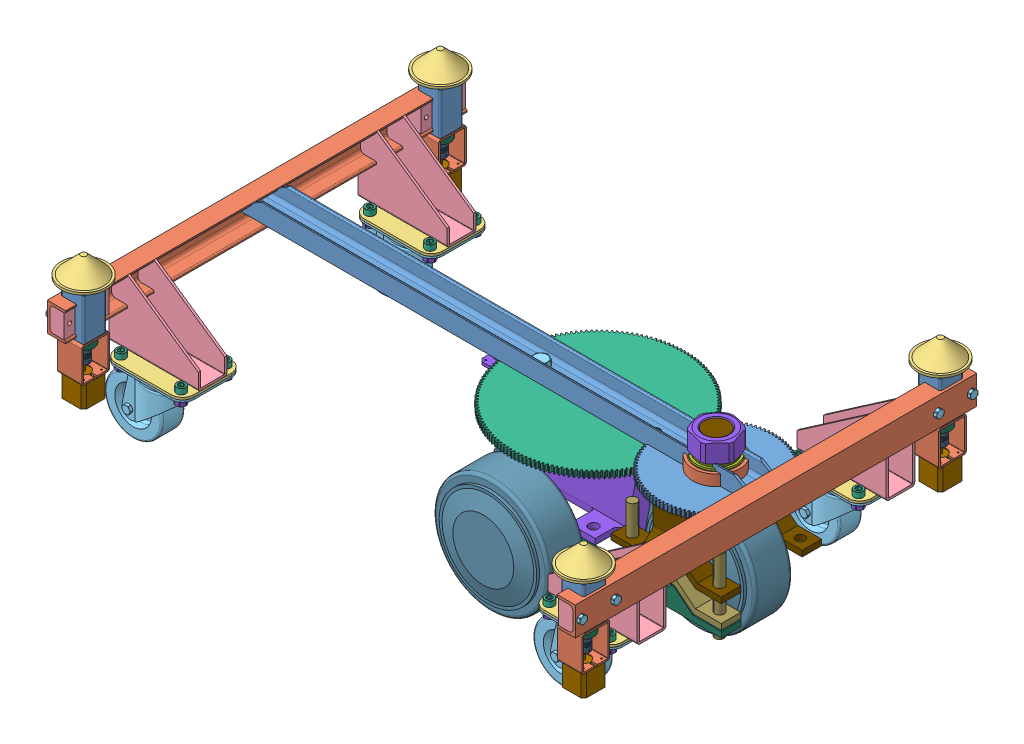
SolidWorks assembly Носитель К3-1, configuration 00. Lengths in mm.
Overall size (950 309 700).
195 component instances, 38 part files, 44 mates.
Components (placement in the parent):
- Каркас несущий К3-1: Каркас несущий К3 [00] at (0 265 0) size (950 309 700)
  - Рама силовая (К2)-1: Рама силовая (К2) [Для смещенного] at origin size (920.8 129.01 700)
    - Хребет продольный-1: Хребет продольный [Смещено вперед] at origin size (912 32 50) (hidden)
    - Балка несущая-1: Балка несущая [00] at (-456 -42.75 0) size (155.33 119.25 700)
      - Швеллер 5У-1: Швеллер 5У [--] at origin size (32 50 700)
      - Кронштейн ленивца-1: Кронштейн ленивца [00] at (82.4347 -94.25 217) size (155.33 119.25 105)
        - Опора ленивца-1: Опора ленивца [--] at origin size (137 4 105)
        - Касынка кронштейна ленивца-1: Касынка кронштейна ленивца [--] at (0 4 0) size (155.33 115.25 50)
      - Кронштейн ленивца-2: Кронштейн ленивца [00] at (82.4347 -94.25 -217) size (155.33 119.25 105)
        - Опора ленивца-1: Опора ленивца [--] at origin size (137 4 105)
        - Касынка кронштейна ленивца-1: Касынка кронштейна ленивца [--] at (0 4 0) size (155.33 115.25 50)
    - Балка несущая-2: Балка несущая [00] at (456 -42.75 0) x (-1 0 0) z (0 0 -1) size (155.33 119.25 700)
      - Швеллер 5У-1: Швеллер 5У [--] at origin size (32 50 700)
      - Кронштейн ленивца-1: Кронштейн ленивца [00] at (82.4347 -94.25 217) size (155.33 119.25 105)
        - Опора ленивца-1: Опора ленивца [--] at origin size (137 4 105)
        - Касынка кронштейна ленивца-1: Касынка кронштейна ленивца [--] at (0 4 0) size (155.33 115.25 50)
      - Кронштейн ленивца-2: Кронштейн ленивца [00] at (82.4347 -94.25 -217) size (155.33 119.25 105)
        - Опора ленивца-1: Опора ленивца [--] at origin size (137 4 105)
        - Касынка кронштейна ленивца-1: Касынка кронштейна ленивца [--] at (0 4 0) size (155.33 115.25 50)
  - АЗ - Колесо ленивец - Tente Alpha 3470 ITP 100 P63-1: АЗ - Колесо ленивец - Tente Alpha 3470 ITP 100 P63 [По умолчанию] at (-373.5653 -137 217) size (202.87 128 202.87)
  - АЗ - Колесо ленивец - Tente Alpha 3470 ITP 100 P63-2: АЗ - Колесо ленивец - Tente Alpha 3470 ITP 100 P63 [По умолчанию] at (373.5653 -137 217) size (202.87 128 202.87)
  - АЗ - Колесо ленивец - Tente Alpha 3470 ITP 100 P63-3: АЗ - Колесо ленивец - Tente Alpha 3470 ITP 100 P63 [По умолчанию] at (373.5653 -137 -217) size (202.87 128 202.87)
  - АЗ - Колесо ленивец - Tente Alpha 3470 ITP 100 P63-4: АЗ - Колесо ленивец - Tente Alpha 3470 ITP 100 P63 [По умолчанию] at (-373.5653 -137 -217) size (202.87 128 202.87)
  - Винты с цилиндрической головкой (ГОСТ 11738-84)-1: Винты с цилиндрической головкой (ГОСТ 11738-84) [Винт М10-(6g)x20 ГОСТ 11738-84] at (-426.0653 -133 255.75) x (0.408379 0 0.912812) z (0 1 0) size (16 16 30.28)
  - Шайбы (ГОСТ 11371-78)-1: Шайбы (ГОСТ 11371-78) [Шайба 10 ГОСТ 11371-78] at (-426.0653 -141.5 255.75) x (0 -1 0) z (0.195759 0 0.980652) size (2 20 20)
  - Гайка (ГОСТ ISO 4032-2014)-1: Гайка (ГОСТ ISO 4032-2014) [Гайка М10 (ГОСТ ISO 4032)] at (-426.0653 -146.7 255.75) x (0.781361 0 0.624079) z (0 1 0) size (16 17.77 8.4)
  - Гайка (ГОСТ ISO 4032-2014)-2: Гайка (ГОСТ ISO 4032-2014) [Гайка М10 (ГОСТ ISO 4032)] at (-321.0653 -146.7 255.75) x (0.884972 0 0.465645) z (0 1 0) size (16 17.77 8.4)
  - Шайбы (ГОСТ 11371-78)-2: Шайбы (ГОСТ 11371-78) [Шайба 10 ГОСТ 11371-78] at (-321.0653 -141.5 255.75) x (0 -1 0) z (0.37706 0 0.926189) size (2 20 20)
  - Винты с цилиндрической головкой (ГОСТ 11738-84)-2: Винты с цилиндрической головкой (ГОСТ 11738-84) [Винт М10-(6g)x20 ГОСТ 11738-84] at (-321.0653 -133 255.75) x (0.573086 0 0.819496) z (0 1 0) size (16 16 30.28)
  - Гайка (ГОСТ ISO 4032-2014)-3: Гайка (ГОСТ ISO 4032-2014) [Гайка М10 (ГОСТ ISO 4032)] at (-321.0653 -146.7 178.25) x (0.964544 0 0.263921) z (0 1 0) size (16 17.77 8.4)
  - Шайбы (ГОСТ 11371-78)-3: Шайбы (ГОСТ 11371-78) [Шайба 10 ГОСТ 11371-78] at (-321.0653 -141.5 178.25) x (0 -1 0) z (0.567856 0 0.823128) size (2 20 20)
  - Винты с цилиндрической головкой (ГОСТ 11738-84)-3: Винты с цилиндрической головкой (ГОСТ 11738-84) [Винт М10-(6g)x20 ГОСТ 11738-84] at (-321.0653 -133 178.25) x (0.736272 0 0.676686) z (0 1 0) size (16 16 30.28)
  - Гайка (ГОСТ ISO 4032-2014)-4: Гайка (ГОСТ ISO 4032-2014) [Гайка М10 (ГОСТ ISO 4032)] at (-426.0653 -146.7 178.25) x (0.999536 0 0.030446) z (0 1 0) size (16 17.77 8.4)
  - Шайбы (ГОСТ 11371-78)-4: Шайбы (ГОСТ 11371-78) [Шайба 10 ГОСТ 11371-78] at (-426.0653 -141.5 178.25) x (0 -1 0) z (0.744998 0 0.667066) size (2 20 20)
  - Винты с цилиндрической головкой (ГОСТ 11738-84)-4: Винты с цилиндрической головкой (ГОСТ 11738-84) [Винт М10-(6g)x20 ГОСТ 11738-84] at (-426.0653 -133 178.25) x (0.874391 0 0.485223) z (0 1 0) size (16 16 30.28)
  - Гайка (ГОСТ ISO 4032-2014)-5: Гайка (ГОСТ ISO 4032-2014) [Гайка М10 (ГОСТ ISO 4032)] at (-426.0653 -146.7 -178.25) x (0.97789 0 -0.209118) z (0 1 0) size (16 17.77 8.4)
  - Шайбы (ГОСТ 11371-78)-5: Шайбы (ГОСТ 11371-78) [Шайба 10 ГОСТ 11371-78] at (-426.0653 -141.5 -178.25) x (0 -1 0) z (0.882737 0 0.469867) size (2 20 20)
  - Винты с цилиндрической головкой (ГОСТ 11738-84)-5: Винты с цилиндрической головкой (ГОСТ 11738-84) [Винт М10-(6g)x20 ГОСТ 11738-84] at (-426.0653 -133 -178.25) x (0.964963 0 0.262386) z (0 1 0) size (16 16 30.28)
  - Гайка (ГОСТ ISO 4032-2014)-6: Гайка (ГОСТ ISO 4032-2014) [Гайка М10 (ГОСТ ISO 4032)] at (-321.0653 -146.7 -178.25) x (0.905941 0 -0.423405) z (0 1 0) size (16 17.77 8.4)
  - Шайбы (ГОСТ 11371-78)-6: Шайбы (ГОСТ 11371-78) [Шайба 10 ГОСТ 11371-78] at (-321.0653 -141.5 -178.25) x (0 -1 0) z (0.965715 0 0.259604) size (2 20 20)
  - Винты с цилиндрической головкой (ГОСТ 11738-84)-6: Винты с цилиндрической головкой (ГОСТ 11738-84) [Винт М10-(6g)x20 ГОСТ 11738-84] at (-321.0653 -133 -178.25) x (0.999241 0 0.038957) z (0 1 0) size (16 16 30.28)
  - Гайка (ГОСТ ISO 4032-2014)-7: Гайка (ГОСТ ISO 4032-2014) [Гайка М10 (ГОСТ ISO 4032)] at (-426.0653 -146.7 -255.75) x (0.807744 0 -0.589534) z (0 1 0) size (16 17.77 8.4)
  - Шайбы (ГОСТ 11371-78)-7: Шайбы (ГОСТ 11371-78) [Шайба 10 ГОСТ 11371-78] at (-426.0653 -141.5 -255.75) x (0 -1 0) z (0.997598 0 0.069276) size (2 20 20)
  - Винты с цилиндрической головкой (ГОСТ 11738-84)-7: Винты с цилиндрической головкой (ГОСТ 11738-84) [Винт М10-(6g)x20 ГОСТ 11738-84] at (-426.0653 -133 -255.75) x (0.988117 0 -0.153703) z (0 1 0) size (16 16 30.28)
  - Гайка (ГОСТ ISO 4032-2014)-8: Гайка (ГОСТ ISO 4032-2014) [Гайка М10 (ГОСТ ISO 4032)] at (-321.0653 -146.7 -255.75) x (0.713458 0 -0.700698) z (0 1 0) size (16 17.77 8.4)
  - Шайбы (ГОСТ 11371-78)-8: Шайбы (ГОСТ 11371-78) [Шайба 10 ГОСТ 11371-78] at (-321.0653 -141.5 -255.75) x (0 -1 0) z (0.997071 0 -0.076488) size (2 20 20)
  - Винты с цилиндрической головкой (ГОСТ 11738-84)-8: Винты с цилиндрической головкой (ГОСТ 11738-84) [Винт М10-(6g)x20 ГОСТ 11738-84] at (-321.0653 -133 -255.75) x (0.955275 0 -0.295719) z (0 1 0) size (16 16 30.28)
  - Гайка (ГОСТ ISO 4032-2014)-9: Гайка (ГОСТ ISO 4032-2014) [Гайка М10 (ГОСТ ISO 4032)] at (321.0653 -146.7 255.75) x (0.647527 0 -0.762043) z (0 1 0) size (16 17.77 8.4)
  - Шайбы (ГОСТ 11371-78)-9: Шайбы (ГОСТ 11371-78) [Шайба 10 ГОСТ 11371-78] at (321.0653 -141.5 255.75) x (0 -1 0) z (0.986146 0 -0.165879) size (2 20 20)
  - Винты с цилиндрической головкой (ГОСТ 11738-84)-9: Винты с цилиндрической головкой (ГОСТ 11738-84) [Винт М10-(6g)x20 ГОСТ 11738-84] at (321.0653 -133 255.75) x (0.924797 0 -0.380462) z (0 1 0) size (16 16 30.28)
  - Гайка (ГОСТ ISO 4032-2014)-10: Гайка (ГОСТ ISO 4032-2014) [Гайка М10 (ГОСТ ISO 4032)] at (426.0653 -146.7 255.75) x (0.624079 0 -0.781361) z (0 1 0) size (16 17.77 8.4)
  - Шайбы (ГОСТ 11371-78)-10: Шайбы (ГОСТ 11371-78) [Шайба 10 ГОСТ 11371-78] at (426.0653 -141.5 255.75) x (0 -1 0) z (0.980652 0 -0.195759) size (2 20 20)
  - Винты с цилиндрической головкой (ГОСТ 11738-84)-10: Винты с цилиндрической головкой (ГОСТ 11738-84) [Винт М10-(6g)x20 ГОСТ 11738-84] at (426.0653 -133 255.75) x (0.912812 0 -0.408379) z (0 1 0) size (16 16 30.28)
  - Гайка (ГОСТ ISO 4032-2014)-11: Гайка (ГОСТ ISO 4032-2014) [Гайка М10 (ГОСТ ISO 4032)] at (321.0653 -146.7 178.25) x (0.647527 0 -0.762043) z (0 1 0) size (16 17.77 8.4)
  - Шайбы (ГОСТ 11371-78)-11: Шайбы (ГОСТ 11371-78) [Шайба 10 ГОСТ 11371-78] at (321.0653 -141.5 178.25) x (0 -1 0) z (0.986146 0 -0.165879) size (2 20 20)
  - Винты с цилиндрической головкой (ГОСТ 11738-84)-11: Винты с цилиндрической головкой (ГОСТ 11738-84) [Винт М10-(6g)x20 ГОСТ 11738-84] at (321.0653 -133 178.25) x (0.924797 0 -0.380462) z (0 1 0) size (16 16 30.28)
  - Гайка (ГОСТ ISO 4032-2014)-12: Гайка (ГОСТ ISO 4032-2014) [Гайка М10 (ГОСТ ISO 4032)] at (426.0653 -146.7 178.25) x (0.713458 0 -0.700698) z (0 1 0) size (16 17.77 8.4)
  - Шайбы (ГОСТ 11371-78)-12: Шайбы (ГОСТ 11371-78) [Шайба 10 ГОСТ 11371-78] at (426.0653 -141.5 178.25) x (0 -1 0) z (0.997071 0 -0.076488) size (2 20 20)
  - Винты с цилиндрической головкой (ГОСТ 11738-84)-12: Винты с цилиндрической головкой (ГОСТ 11738-84) [Винт М10-(6g)x20 ГОСТ 11738-84] at (426.0653 -133 178.25) x (0.955275 0 -0.295719) z (0 1 0) size (16 16 30.28)
  - Гайка (ГОСТ ISO 4032-2014)-13: Гайка (ГОСТ ISO 4032-2014) [Гайка М10 (ГОСТ ISO 4032)] at (321.0653 -146.7 -178.25) x (0.807744 0 -0.589534) z (0 1 0) size (16 17.77 8.4)
  - Шайбы (ГОСТ 11371-78)-13: Шайбы (ГОСТ 11371-78) [Шайба 10 ГОСТ 11371-78] at (321.0653 -141.5 -178.25) x (0 -1 0) z (0.997598 0 0.069276) size (2 20 20)
  - Винты с цилиндрической головкой (ГОСТ 11738-84)-13: Винты с цилиндрической головкой (ГОСТ 11738-84) [Винт М10-(6g)x20 ГОСТ 11738-84] at (321.0653 -133 -178.25) x (0.988117 0 -0.153703) z (0 1 0) size (16 16 30.28)
  - Гайка (ГОСТ ISO 4032-2014)-14: Гайка (ГОСТ ISO 4032-2014) [Гайка М10 (ГОСТ ISO 4032)] at (426.0653 -146.7 -178.25) x (0.905941 0 -0.423405) z (0 1 0) size (16 17.77 8.4)
  - Шайбы (ГОСТ 11371-78)-14: Шайбы (ГОСТ 11371-78) [Шайба 10 ГОСТ 11371-78] at (426.0653 -141.5 -178.25) x (0 -1 0) z (0.965715 0 0.259604) size (2 20 20)
  - Винты с цилиндрической головкой (ГОСТ 11738-84)-14: Винты с цилиндрической головкой (ГОСТ 11738-84) [Винт М10-(6g)x20 ГОСТ 11738-84] at (426.0653 -133 -178.25) x (0.999241 0 0.038957) z (0 1 0) size (16 16 30.28)
  - Гайка (ГОСТ ISO 4032-2014)-15: Гайка (ГОСТ ISO 4032-2014) [Гайка М10 (ГОСТ ISO 4032)] at (321.0653 -146.7 -255.75) x (0.97789 0 -0.209118) z (0 1 0) size (16 17.77 8.4)
  - Шайбы (ГОСТ 11371-78)-15: Шайбы (ГОСТ 11371-78) [Шайба 10 ГОСТ 11371-78] at (321.0653 -141.5 -255.75) x (0 -1 0) z (0.882737 0 0.469867) size (2 20 20)
  - Винты с цилиндрической головкой (ГОСТ 11738-84)-15: Винты с цилиндрической головкой (ГОСТ 11738-84) [Винт М10-(6g)x20 ГОСТ 11738-84] at (321.0653 -133 -255.75) x (0.964963 0 0.262386) z (0 1 0) size (16 16 30.28)
  - Гайка (ГОСТ ISO 4032-2014)-16: Гайка (ГОСТ ISO 4032-2014) [Гайка М10 (ГОСТ ISO 4032)] at (426.0653 -146.7 -255.75) x (0.999536 0 0.030446) z (0 1 0) size (16 17.77 8.4)
  - Шайбы (ГОСТ 11371-78)-16: Шайбы (ГОСТ 11371-78) [Шайба 10 ГОСТ 11371-78] at (426.0653 -141.5 -255.75) x (0 -1 0) z (0.744998 0 0.667066) size (2 20 20)
  - Винты с цилиндрической головкой (ГОСТ 11738-84)-16: Винты с цилиндрической головкой (ГОСТ 11738-84) [Винт М10-(6g)x20 ГОСТ 11738-84] at (426.0653 -133 -255.75) x (0.874391 0 0.485223) z (0 1 0) size (16 16 30.28)
  - Линейный движитель-1: Линейный движитель [00] at (-436 -133 311) x (1 0 0) z (0 1 0) size (78 78 215)
    - 17HS4401 (Nema17)-1: 17HS4401 (Nema17) [--] at origin size (42.3 42.3 63.5)
    - Муфта гибкая-1: Муфта гибкая [--] at (0 0 42.25) size (20 20 26)
    - Винт CS М12х2х150-1: Винт CS М12х2х150 [--] at (0 0 133) x (0.999367 0.035585 0) z (0 0 1) size (12 12.62 100)
    - Упор винта-1: Упор винта [--] at (0 0 57.25) size (14 14 13)
    - Подшипник упорный 8100-1: Подшипник упорный 8100 [--] at (0 0 48.25) x (1 0 0) z (0 -1 0) size (24 9 24)
    - Стопор внутренний до 165мм (ГОСТ 13943-86)-1: Стопор внутренний до 165мм (ГОСТ 13943-86) [Кольцо 24] at (0 0 47.05) size (25.5 26.7 1.2)
    - Обойма под 8100-1: Обойма под 8100 [--] at (0 0 48.25) size (35 35 16.2)
    - Гайка DCM12-1: Гайка DCM12 [Доработка] at (0 0 64.25) x (0 0 1) z (-0.707107 -0.707107 0) size (30.72 41.36 41.36)
    - Профильная труба 35х35х2-1: Профильная труба 35х35х2 [--] at (0 0 74.25) size (35 35 68.75)
    - Заглушка35х35-1: Заглушка35х35 [--] at (0 0 70.25) size (35 35 4)
    - Профильная труба 40х40х2-1: Профильная труба 40х40х2 [--] at (0 0 60.25) size (40 40 72.75)
    - Заглушка 40х40-1: Заглушка 40х40 [--] at (0 0 60.25) size (42.3 48.3 60.25)
    - Уловитель-1: Уловитель [--] at (0 0 143) size (78 78 39)
    - Фиксатор-1: Фиксатор [--] at (-20 -20 60.25) x (0 1 0) z (1 0 0) size (19 41.2 25.1)
    - Фиксатор-2: Фиксатор [--] at (-20 39 60.25) x (0 1 0) z (1 0 0) size (19 41.2 25.1)
  - Болты с шестигранной головкой кт.В (ГОСТ 7798-70)-1: Болты с шестигранной головкой кт.В (ГОСТ 7798-70) [Болт М8-6gx25(S13) ГОСТ 7798-77] at (-460.4 -42.75 340.5) size (30.3 14.2 13)
  - Болты с шестигранной головкой кт.В (ГОСТ 7798-70)-2: Болты с шестигранной головкой кт.В (ГОСТ 7798-70) [Болт М8-6gx25(S13) ГОСТ 7798-77] at (-460.4 -42.75 281.5) x (1 0 0) z (0 -0.158553 0.987351) size (30.3 14.2 13)
  - Линейный движитель-2: Линейный движитель [00] at (-436 -133 -311) x (1 0 0) z (0 1 0) size (78 78 215)
    - 17HS4401 (Nema17)-1: 17HS4401 (Nema17) [--] at origin size (42.3 42.3 63.5)
    - Муфта гибкая-1: Муфта гибкая [--] at (0 0 42.25) size (20 20 26)
    - Винт CS М12х2х150-1: Винт CS М12х2х150 [--] at (0 0 133) x (0.999367 0.035585 0) z (0 0 1) size (12 12.62 100)
    - Упор винта-1: Упор винта [--] at (0 0 57.25) size (14 14 13)
    - Подшипник упорный 8100-1: Подшипник упорный 8100 [--] at (0 0 48.25) x (1 0 0) z (0 -1 0) size (24 9 24)
    - Стопор внутренний до 165мм (ГОСТ 13943-86)-1: Стопор внутренний до 165мм (ГОСТ 13943-86) [Кольцо 24] at (0 0 47.05) size (25.5 26.7 1.2)
    - Обойма под 8100-1: Обойма под 8100 [--] at (0 0 48.25) size (35 35 16.2)
    - Гайка DCM12-1: Гайка DCM12 [Доработка] at (0 0 64.25) x (0 0 1) z (-0.707107 -0.707107 0) size (30.72 41.36 41.36)
    - Профильная труба 35х35х2-1: Профильная труба 35х35х2 [--] at (0 0 74.25) size (35 35 68.75)
    - Заглушка35х35-1: Заглушка35х35 [--] at (0 0 70.25) size (35 35 4)
    - Профильная труба 40х40х2-1: Профильная труба 40х40х2 [--] at (0 0 60.25) size (40 40 72.75)
    - Заглушка 40х40-1: Заглушка 40х40 [--] at (0 0 60.25) size (42.3 48.3 60.25)
    - Уловитель-1: Уловитель [--] at (0 0 143) size (78 78 39)
    - Фиксатор-1: Фиксатор [--] at (-20 -20 60.25) x (0 1 0) z (1 0 0) size (19 41.2 25.1)
    - Фиксатор-2: Фиксатор [--] at (-20 39 60.25) x (0 1 0) z (1 0 0) size (19 41.2 25.1)
  - Болты с шестигранной головкой кт.В (ГОСТ 7798-70)-4: Болты с шестигранной головкой кт.В (ГОСТ 7798-70) [Болт М8-6gx25(S13) ГОСТ 7798-77] at (-460.4 -42.75 -281.5) size (30.3 14.2 13)
  - Болты с шестигранной головкой кт.В (ГОСТ 7798-70)-5: Болты с шестигранной головкой кт.В (ГОСТ 7798-70) [Болт М8-6gx25(S13) ГОСТ 7798-77] at (-460.4 -42.75 -340.5) x (1 0 0) z (0 -0.158553 0.987351) size (30.3 14.2 13)
  - Линейный движитель-5: Линейный движитель [00] at (436 -133 311) x (-1 0 0) z (0 1 0) size (78 78 215)
    - 17HS4401 (Nema17)-1: 17HS4401 (Nema17) [--] at origin size (42.3 42.3 63.5)
    - Муфта гибкая-1: Муфта гибкая [--] at (0 0 42.25) size (20 20 26)
    - Винт CS М12х2х150-1: Винт CS М12х2х150 [--] at (0 0 133) x (0.999367 0.035585 0) z (0 0 1) size (12 12.62 100)
    - Упор винта-1: Упор винта [--] at (0 0 57.25) size (14 14 13)
    - Подшипник упорный 8100-1: Подшипник упорный 8100 [--] at (0 0 48.25) x (1 0 0) z (0 -1 0) size (24 9 24)
    - Стопор внутренний до 165мм (ГОСТ 13943-86)-1: Стопор внутренний до 165мм (ГОСТ 13943-86) [Кольцо 24] at (0 0 47.05) size (25.5 26.7 1.2)
    - Обойма под 8100-1: Обойма под 8100 [--] at (0 0 48.25) size (35 35 16.2)
    - Гайка DCM12-1: Гайка DCM12 [Доработка] at (0 0 64.25) x (0 0 1) z (-0.707107 -0.707107 0) size (30.72 41.36 41.36)
    - Профильная труба 35х35х2-1: Профильная труба 35х35х2 [--] at (0 0 74.25) size (35 35 68.75)
    - Заглушка35х35-1: Заглушка35х35 [--] at (0 0 70.25) size (35 35 4)
    - Профильная труба 40х40х2-1: Профильная труба 40х40х2 [--] at (0 0 60.25) size (40 40 72.75)
    - Заглушка 40х40-1: Заглушка 40х40 [--] at (0 0 60.25) size (42.3 48.3 60.25)
    - Уловитель-1: Уловитель [--] at (0 0 143) size (78 78 39)
    - Фиксатор-1: Фиксатор [--] at (-20 -20 60.25) x (0 1 0) z (1 0 0) size (19 41.2 25.1)
    - Фиксатор-2: Фиксатор [--] at (-20 39 60.25) x (0 1 0) z (1 0 0) size (19 41.2 25.1)
  - Болты с шестигранной головкой кт.В (ГОСТ 7798-70)-10: Болты с шестигранной головкой кт.В (ГОСТ 7798-70) [Болт М8-6gx25(S13) ГОСТ 7798-77] at (460.4 -42.75 281.5) x (-1 0 0) z (0 0 -1) size (30.3 14.2 13)
  - Болты с шестигранной головкой кт.В (ГОСТ 7798-70)-11: Болты с шестигранной головкой кт.В (ГОСТ 7798-70) [Болт М8-6gx25(S13) ГОСТ 7798-77] at (460.4 -42.75 340.5) x (-1 0 0) z (0 -0.158553 -0.987351) size (30.3 14.2 13)
  - Линейный движитель-7: Линейный движитель [00] at (436 -133 -311) x (-1 0 0) z (0 1 0) size (78 78 215)
    - 17HS4401 (Nema17)-1: 17HS4401 (Nema17) [--] at origin size (42.3 42.3 63.5)
    - Муфта гибкая-1: Муфта гибкая [--] at (0 0 42.25) size (20 20 26)
    - Винт CS М12х2х150-1: Винт CS М12х2х150 [--] at (0 0 133) x (0.999367 0.035585 0) z (0 0 1) size (12 12.62 100)
    - Упор винта-1: Упор винта [--] at (0 0 57.25) size (14 14 13)
    - Подшипник упорный 8100-1: Подшипник упорный 8100 [--] at (0 0 48.25) x (1 0 0) z (0 -1 0) size (24 9 24)
    - Стопор внутренний до 165мм (ГОСТ 13943-86)-1: Стопор внутренний до 165мм (ГОСТ 13943-86) [Кольцо 24] at (0 0 47.05) size (25.5 26.7 1.2)
    - Обойма под 8100-1: Обойма под 8100 [--] at (0 0 48.25) size (35 35 16.2)
    - Гайка DCM12-1: Гайка DCM12 [Доработка] at (0 0 64.25) x (0 0 1) z (-0.707107 -0.707107 0) size (30.72 41.36 41.36)
    - Профильная труба 35х35х2-1: Профильная труба 35х35х2 [--] at (0 0 74.25) size (35 35 68.75)
    - Заглушка35х35-1: Заглушка35х35 [--] at (0 0 70.25) size (35 35 4)
    - Профильная труба 40х40х2-1: Профильная труба 40х40х2 [--] at (0 0 60.25) size (40 40 72.75)
    - Заглушка 40х40-1: Заглушка 40х40 [--] at (0 0 60.25) size (42.3 48.3 60.25)
    - Уловитель-1: Уловитель [--] at (0 0 143) size (78 78 39)
    - Фиксатор-1: Фиксатор [--] at (-20 -20 60.25) x (0 1 0) z (1 0 0) size (19 41.2 25.1)
    - Фиксатор-2: Фиксатор [--] at (-20 39 60.25) x (0 1 0) z (1 0 0) size (19 41.2 25.1)
  - Болты с шестигранной головкой кт.В (ГОСТ 7798-70)-14: Болты с шестигранной головкой кт.В (ГОСТ 7798-70) [Болт М8-6gx25(S13) ГОСТ 7798-77] at (460.4 -42.75 -340.5) x (-1 0 0) z (0 0 -1) size (30.3 14.2 13)
  - Болты с шестигранной головкой кт.В (ГОСТ 7798-70)-15: Болты с шестигранной головкой кт.В (ГОСТ 7798-70) [Болт М8-6gx25(S13) ГОСТ 7798-77] at (460.4 -42.75 -281.5) x (-1 0 0) z (0 -0.158553 -0.987351) size (30.3 14.2 13)
  - Шестерня большая-2: Шестерня большая [Z150] at (150 -39.99 0) x (0 -1 0) z (0 0 -1) size (87 303.96 304) (hidden)
  - Болты с шестигранной головкой кт.В (ГОСТ 7798-70)-18: Болты с шестигранной головкой кт.В (ГОСТ 7798-70) [*Болт М16-6gx18(S24) ГОСТ 7798-77] at (50 -35.59 0) x (0 -1 0) z (-0.995564 0 0.094084) size (28 26.2 24) (hidden)
  - Болты с шестигранной головкой кт.В (ГОСТ 7798-70)-19: Болты с шестигранной головкой кт.В (ГОСТ 7798-70) [*Болт М16-6gx18(S24) ГОСТ 7798-77] at (250 -35.59 0) x (0 -1 0) z (-0.959995 0 0.280017) size (28 26.2 24) (hidden)
- Подшипник 2007910А (72х50х15)-1: Подшипник 2007910А (72х50х15) [--] at (150 202.01 0) x (0 1 0) z (-0.845753 0 0.533575) size (15 72 72) (hidden)
- Кронштейн ступицы поворотной-1: Кронштейн ступицы поворотной [00] at (150 199.51 0) size (372.3 178 210.07) (hidden)
  - Каретка-1: Каретка [--] at origin size (372.3 98.5 202)
  - Обойма 2007910А (2шт)-1: Обойма 2007910А (2шт) [--] at (0 -2.5 0) x (0 -1 0) z (-0.634197 0 -0.773171) size (47 82 82)
  - Линейный подшипник (16х30х40)-1: Линейный подшипник (16х30х40) [--] at (-76 -63.5 84) x (-0.966713 0 0.255864) z (0 -1 0) size (30 30 40)
  - Линейный подшипник (16х30х40)-2: Линейный подшипник (16х30х40) [--] at (76 -63.5 84) x (-0.901172 0 0.433461) z (0 -1 0) size (30 30 40)
  - Линейный подшипник (16х30х40)-3: Линейный подшипник (16х30х40) [--] at (76 -63.5 -84) x (-0.786541 0 0.617538) z (0 -1 0) size (30 30 40)
  - Линейный подшипник (16х30х40)-4: Линейный подшипник (16х30х40) [--] at (-76 -63.5 -84) x (-0.619852 0 0.784719) z (0 -1 0) size (30 30 40)
  - Пружина 22х22х2-1: Пружина 22х22х2 [--] at (76 -93.75 -84) x (-0.837169 0 -0.546944) z (-0.546944 0 0.837169) size (24 22 24.59)
  - Пружина 22х22х2-2: Пружина 22х22х2 [--] at (-76 -93.75 -84) x (-0.925243 0 -0.379375) z (-0.379375 0 0.925243) size (24 22 24.59)
  - Пружина 22х22х2-3: Пружина 22х22х2 [--] at (-76 -93.75 84) x (-0.985271 0 -0.170998) z (-0.170998 0 0.985271) size (24 22 24.59)
  - Пружина 22х22х2-4: Пружина 22х22х2 [--] at (76 -93.75 84) x (-0.997902 0 0.064746) z (0.064746 0 0.997902) size (24 22 24.59)
  - Верхний кронштейн К2-1: Верхний кронштейн К2 [--] at (0 -99.5 -67) size (192 129 34)
  - Верхний кронштейн К2-2: Верхний кронштейн К2 [--] at (0 -99.5 101) size (192 129 34)
  - Шайбы (ГОСТ 11371-78)-1: Шайбы (ГОСТ 11371-78) [Шайба 16 ГОСТ 11371-78] at (76 -42 -84) x (0 -1 0) z (0 0 1) size (3 30 30)
  - Гайка (ГОСТ ISO 4032-2014)-1: Гайка (ГОСТ ISO 4032-2014) [Гайка М16 (ГОСТ ISO 4032)] at (76 -33.1 -84) x (0.816213 0 0.577751) z (0 1 0) size (24 26.75 14.8)
  - Гайка (ГОСТ ISO 4032-2014)-2: Гайка (ГОСТ ISO 4032-2014) [Гайка М16 (ГОСТ ISO 4032)] at (-76 -33.1 -84) x (0.910468 0 0.413579) z (0 1 0) size (24 26.75 14.8)
  - Шайбы (ГОСТ 11371-78)-2: Шайбы (ГОСТ 11371-78) [Шайба 16 ГОСТ 11371-78] at (-76 -42 -84) x (0 -1 0) z (0.188455 0 0.982082) size (3 30 30)
  - Гайка (ГОСТ ISO 4032-2014)-4: Гайка (ГОСТ ISO 4032-2014) [Гайка М16 (ГОСТ ISO 4032)] at (-76 -33.1 84) x (0.978217 0 0.207583) z (0 1 0) size (24 26.75 14.8)
  - Шайбы (ГОСТ 11371-78)-4: Шайбы (ГОСТ 11371-78) [Шайба 16 ГОСТ 11371-78] at (-76 -42 84) x (0 -1 0) z (0.395734 0 0.918365) size (3 30 30)
  - Гайка (ГОСТ ISO 4032-2014)-6: Гайка (ГОСТ ISO 4032-2014) [Гайка М16 (ГОСТ ISO 4032)] at (76 -33.1 84) x (0.999621 0 -0.027527) z (0 1 0) size (24 26.75 14.8)
  - Шайбы (ГОСТ 11371-78)-6: Шайбы (ГОСТ 11371-78) [Шайба 16 ГОСТ 11371-78] at (76 -42 84) x (0 -1 0) z (0.6 0 0.8) size (3 30 30)
  - 17HS4401 (Nema17)-1: 17HS4401 (Nema17) [--] at (-165 0 0) x (1 0 0) z (0 1 0) size (42.3 42.3 63.5)
- Шестерня малая-4: Шестерня малая [DIN - Spur gear 2M 15T 20PA 10FW ---S15B15H23L5N] at (-15 215.01 0) x (0 1 0) z (0.147192 0 0.989108) size (23 33.72 33.9) (hidden)
- Мотор-колесо ZLLG80ASM800-2: Мотор-колесо ZLLG80ASM800 [1 крепление] at (150 100.01 154.5) x (0 0 1) z (0 1 0) size (133 200 200) (hidden)
- Прижим К2-1: Прижим К2 [--] at (150 100.01 101) size (192 37 34) (hidden)
- Гайка (ГОСТ ISO 4032-2014)-1: Гайка (ГОСТ ISO 4032-2014) [Гайка М16 (ГОСТ ISO 4032)] at (226 54.61 84) x (-0.815496 0 0.578763) z (0 -1 0) size (24 26.75 14.8) (hidden)
- Гайка (ГОСТ ISO 4032-2014)-2: Гайка (ГОСТ ISO 4032-2014) [Гайка М16 (ГОСТ ISO 4032)] at (74 54.61 84) x (-0.691813 0 0.722077) z (0 -1 0) size (24 26.75 14.8) (hidden)
- Гайка (ГОСТ ISO 4032-2014)-5: Гайка (ГОСТ ISO 4032-2014) [Гайка М16 (ГОСТ ISO 4032)] at (74 54.61 -84) x (-0.691813 0 0.722077) z (0 -1 0) size (24 26.75 14.8) (hidden)
- Прижим К2-2: Прижим К2 [--] at (150 100.01 -67) size (192 37 34) (hidden)
- Мотор-колесо ZLLG80ASM800-3: Мотор-колесо ZLLG80ASM800 [1 крепление] at (150 100.01 -154.5) x (0 0 -1) z (0 1 0) size (133 200 200) (hidden)
- Гайка (ГОСТ ISO 4032-2014)-6: Гайка (ГОСТ ISO 4032-2014) [Гайка М16 (ГОСТ ISO 4032)] at (226 54.61 -84) x (-0.815496 0 0.578763) z (0 -1 0) size (24 26.75 14.8) (hidden)
- Подшипник 2007910А (72х50х15)-2: Подшипник 2007910А (72х50х15) [--] at (150 197.01 0) x (0 -1 0) z (-0.971836 0 0.235658) size (15 72 72) (hidden)
- Кольцо ступицы-1: Кольцо ступицы [--] at (150 177.01 0) x (-0.975842 0 0.218478) z (0.218478 0 0.975842) size (61.75 5 61.75) (hidden)
- Гайка (ГОСТ ISO 4032-2014)-9: Гайка (ГОСТ ISO 4032-2014) [Гайка М42 (ГОСТ ISO 4032)] at (150 160.01 0) x (-0.987419 0 0.158123) z (0 -1 0) size (65 71.3 34) (hidden)
- Привод поворотный (мод 2)-1: Привод поворотный (мод 2) [00] at (356.4 100 0) x (0 0 -1) z (1 0 0) size (232.47 289 236.15)
  - Мотор-колесо ZLLG80ASM800-1: Мотор-колесо ZLLG80ASM800 [По умолчанию] x (1 0 0) z (0 1 0) size (175 200 200)
  - Верхний кронштейн К2-1: Верхний кронштейн К2 [--] at (-53.5 0 0) x (0 0 -1) z (1 0 0) size (192 129 34)
  - Прижим К2-1: Прижим К2 [--] at (-53.5 0 0) x (0 0 -1) z (1 0 0) size (192 37 34)
  - Пружина 14х30-1: Пружина 14х30 [--] at (-70.5 -16 -76) size (22.41 30 22.54)
  - Кулак-1: Кулак [--] at (-87.5 14 0) x (0 0 -1) z (1 0 0) size (232.15 174 175)
  - Подшипник 2007910А (72х50х15)-1: Подшипник 2007910А (72х50х15) [--] at (0 130 0) x (0 -1 0) z (0 0 1) size (15 72 72)
  - Подшипник 2007910А (72х50х15)-3: Подшипник 2007910А (72х50х15) [--] at (0 135 0) x (0 1 0) z (-0.408326 0 0.912836) size (15 72 72)
  - Половинная звезда z100(2)-2: Половинная звезда z100(2) [DIN - Spur gear 2M 100T 20PA 10FW ---S100A75H50L0.2N] at (0 128 0) x (0 -1 0) z (0 0 1) size (41.2 232.47 201.57)
  - Обойма ступицы-1: Обойма ступицы [--] at (0 115 0) size (82 29 82)
  - Кольцо ступицы-1: Кольцо ступицы [--] at (0 155 0) x (0.827904 0 0.56087) z (-0.56087 0 0.827904) size (61.75 5 61.75)
  - Гайка (ГОСТ ISO 4032-2014)-1: Гайка (ГОСТ ISO 4032-2014) [Гайка М42 (ГОСТ ISO 4032)] at (0 172 0) x (-0.974958 0 -0.222391) z (0 -1 0) size (65 71.3 34)
  - Шестерня малая-1: Шестерня малая [DIN - Spur gear 2M 15T 20PA 10FW ---S15B15H23L5N] at (0 118 -115) x (0 1 0) z (0 0 1) size (23 33.72 33.9)
  - 17HS4401 (Nema17)-1: 17HS4401 (Nema17) [--] at (0 105 -115) x (0 0 -1) z (0 1 0) size (42.3 42.3 63.5)
Mates (geometry in assembly coordinates):
- Касательность1: tangent: cylinder of Каркас несущий К3-1/АЗ - Колесо ленивец - Tente Alpha 3470 ITP 100 P63-2 through (323.5653 50 197) axis (0 0 1) radius 50; plane of assembly through (0 0 0) normal (0 1 0)
- Параллельность1: parallel: plane of Каркас несущий К3-1/Шестерня большая-2 through (150 225.01 0) normal (0 1 0)
- Совпадение1: coincident: plane of Каркас несущий К3-1/Рама силовая (К2)-1/Хребет продольный-1 through (0 265 0) normal (0 0 1); plane of assembly through (0 0 0) normal (0 0 1)
- Совпадение2: coincident: plane of Каркас несущий К3-1/Рама силовая (К2)-1/Хребет продольный-1 through (0 265 0) normal (1 0 0); plane of assembly through (0 0 0) normal (1 0 0)
- Совпадение3: coincident: plane of Каркас несущий К3-1/Шестерня большая-2 through (136.8029 217.01 31.9421) normal (0 -1 0); plane of Подшипник 2007910А (72х50х15)-1 through (131.5591 217.01 -29.2301) normal (0 1 0)
- Концентричный1: concentric: cylinder of Подшипник 2007910А (72х50х15)-1 through (150 -797.99 0) axis (0 -1 0) radius 25; cylinder of Каркас несущий К3-1/Шестерня большая-2 through (150 111.2993 0) axis (0 1 0) radius 25
- Совпадение4: coincident: plane of Подшипник 2007910А (72х50х15)-1 through (131.1115 202.01 -29.9397) normal (0 -1 0); plane of Кронштейн ступицы поворотной-1/Обойма 2007910А (2шт)-1 through (122.1658 202.01 22.8311) normal (0 1 0)
- Концентричный2: concentric: cylinder of Подшипник 2007910А (72х50х15)-1 through (150 -797.99 0) axis (0 -1 0) radius 36; cylinder of Кронштейн ступицы поворотной-1/Обойма 2007910А (2шт)-1 through (150 1197.01 0) axis (0 1 0) radius 36
- Совпадение5: coincident: plane of Кронштейн ступицы поворотной-1/17HS4401 (Nema17)-1 through (-15 225.01 0) normal (0 1 0); plane of Шестерня малая-4 through (-15 225.01 0) normal (0 1 0)
- Концентричный3: concentric: cylinder of Кронштейн ступицы поворотной-1/17HS4401 (Nema17)-1 through (-15 225.01 0) axis (0 -1 0) radius 2.5; cylinder of Шестерня малая-4 through (-15 238.0101 0) axis (0 -1 0) radius 2.5
- Совпадение6: coincident: plane of Кронштейн ступицы поворотной-1/Верхний кронштейн К2-1 through (177.7485 106.01 -103.8322) normal (0 -1 0); plane of ? through (-140437.6755 106.01 -255540.1748) normal (0 1 0)
- Совпадение7: coincident: plane of Кронштейн ступицы поворотной-1/Верхний кронштейн К2-1; plane of ? through (88.4913 100.01 -48.6857) normal (-0.876151 0 0.482036)
- Концентричный4: concentric: cylinder of Кронштейн ступицы поворотной-1/Верхний кронштейн К2-1 through (180.2992 100.01 -99.1961) axis (-0.876151 0 0.482036) radius 8; cylinder of ? through (1006.1753 100.01 -553.5723) axis (0.876151 0 -0.482036) radius 8
- Угол1: planar angle = 0 rad: plane of Кронштейн ступицы поворотной-1/Верхний кронштейн К2-2 through (150 100.01 101) normal (0 0 1); plane of Каркас несущий К3-1/Рама силовая (К2)-1/Хребет продольный-1 through (-515.3633 225.01 25) normal (0 0 1)
- Концентричный5: concentric: cylinder of Кронштейн ступицы поворотной-1/Верхний кронштейн К2-2 through (150 100.01 -37.7855) axis (0 0 1) radius 8; cylinder of Мотор-колесо ZLLG80ASM800-2 through (150 100.01 -946.4037) axis (0 0 -1) radius 8
- Совпадение8: coincident: plane of Кронштейн ступицы поворотной-1/Верхний кронштейн К2-2 through (144.7085 106.01 -37.7855) normal (0 -1 0); plane of Мотор-колесо ZLLG80ASM800-2 through (-291437.9 106.01 67) normal (0 1 0)
- Совпадение9: coincident: plane of Кронштейн ступицы поворотной-1/Верхний кронштейн К2-2 through (150 100.01 101) normal (0 0 1); plane of Мотор-колесо ZLLG80ASM800-2 through (150 100.01 101) normal (0 0 -1)
- Совпадение10: coincident: plane of Мотор-колесо ZLLG80ASM800-2 through (-291437.9 94.01 67) normal (0 -1 0); plane of Прижим К2-1 through (150 94.01 -37.7855) normal (0 1 0)
- Концентричный6: concentric: cylinder of Кронштейн ступицы поворотной-1/Верхний кронштейн К2-2 through (74 218.6374 84) axis (0 -1 0) radius 8; cylinder of Прижим К2-1 through (74 96.0516 84) axis (0 -1 0) radius 8.5
- Концентричный7: concentric: cylinder of Кронштейн ступицы поворотной-1/Верхний кронштейн К2-2 through (226 218.6374 84) axis (0 -1 0) radius 8; cylinder of Прижим К2-1 through (226 96.0516 84) axis (0 -1 0) radius 8.5
- Совпадение11: coincident: plane of Прижим К2-1 through (150 62.01 -37.7855) normal (0 -1 0); plane of Гайка (ГОСТ ISO 4032-2014)-1 through (219.4889 62.01 74.8257) normal (0 1 0)
- Концентричный8: concentric: cylinder of Прижим К2-1 through (226 96.0516 84) axis (0 -1 0) radius 8.5; cylinder of Гайка (ГОСТ ISO 4032-2014)-1 through (226 -98.1302 84) axis (0 -1 0) radius 6.2679
- Совпадение12: coincident: plane of Прижим К2-1 through (150 62.01 -37.7855) normal (0 -1 0); plane of Гайка (ГОСТ ISO 4032-2014)-2 through (65.8766 62.01 76.2171) normal (0 1 0)
- Концентричный9: concentric: cylinder of Прижим К2-1 through (74 96.0516 84) axis (0 -1 0) radius 8.5; cylinder of Гайка (ГОСТ ISO 4032-2014)-2 through (74 -98.1302 84) axis (0 -1 0) radius 6.2679
- Совпадение13: coincident: plane of Прижим К2-1 through (0 62.01 -37.7855) normal (0 -1 0); plane of ? through (79.1237 62.01 94.786) normal (0 1 0)
- Совпадение15: coincident: plane of Прижим К2-2 through (150 94.01 -205.7855) normal (0 1 0); plane of Мотор-колесо ZLLG80ASM800-3 through (291737.9 94.01 -67) normal (0 -1 0)
- Совпадение16: coincident: plane of Прижим К2-2 through (150 62.01 -205.7855) normal (0 -1 0); plane of Гайка (ГОСТ ISO 4032-2014)-6 through (219.4889 62.01 -93.1743) normal (0 1 0)
- Концентричный10: concentric: cylinder of Прижим К2-2 through (226 96.0516 -84) axis (0 -1 0) radius 8.5; cylinder of Гайка (ГОСТ ISO 4032-2014)-6 through (226 -98.1302 -84) axis (0 -1 0) radius 6.2679
- Совпадение17: coincident: plane of Гайка (ГОСТ ISO 4032-2014)-5 through (65.8766 62.01 -91.7829) normal (0 1 0); plane of Прижим К2-2 through (150 62.01 -205.7855) normal (0 -1 0)
- Концентричный11: concentric: cylinder of Гайка (ГОСТ ISO 4032-2014)-5 through (74 -98.1302 -84) axis (0 -1 0) radius 6.2679; cylinder of Прижим К2-2 through (74 96.0516 -84) axis (0 -1 0) radius 8.5
- Концентричный12: concentric: cylinder of Кронштейн ступицы поворотной-1/Верхний кронштейн К2-1 through (150 100.01 -205.7855) axis (0 0 1) radius 8; cylinder of Мотор-колесо ZLLG80ASM800-3 through (150 100.01 946.4037) axis (0 0 1) radius 8
- Совпадение18: coincident: plane of Кронштейн ступицы поворотной-1/Верхний кронштейн К2-1 through (144.7085 106.01 -205.7855) normal (0 -1 0); plane of Мотор-колесо ZLLG80ASM800-3 through (291737.9 106.01 -67) normal (0 1 0)
- Совпадение19: coincident: plane of Кронштейн ступицы поворотной-1/Верхний кронштейн К2-1 through (158 100.01 -101) normal (0 0 -1); plane of Мотор-колесо ZLLG80ASM800-3 through (150 100.01 -101) normal (0 0 1)
- Концентричный14: concentric: cylinder of Кронштейн ступицы поворотной-1/Верхний кронштейн К2-1 through (74 218.6374 -84) axis (0 -1 0) radius 8; cylinder of Прижим К2-2 through (74 96.0516 -84) axis (0 -1 0) radius 8.5
- Концентричный15: concentric: cylinder of Кронштейн ступицы поворотной-1/Верхний кронштейн К2-1 through (226 218.6374 -84) axis (0 -1 0) radius 8; cylinder of Прижим К2-2 through (226 96.0516 -84) axis (0 -1 0) radius 8.5
- Совпадение23: coincident: plane of Кронштейн ступицы поворотной-1/Обойма 2007910А (2шт)-1 through (125.2585 197.01 20.2943) normal (0 -1 0); plane of Подшипник 2007910А (72х50х15)-2 through (158.3423 197.01 34.403) normal (0 1 0)
- Концентричный18: concentric: cylinder of Кронштейн ступицы поворотной-1/Обойма 2007910А (2шт)-1 through (150 1197.01 0) axis (0 1 0) radius 36; cylinder of Подшипник 2007910А (72х50х15)-2 through (150 1197.01 0) axis (0 1 0) radius 36
- Совпадение24: coincident: plane of Подшипник 2007910А (72х50х15)-2 through (158.1446 182.01 33.5876) normal (0 -1 0); plane of Кольцо ступицы-1 through (143.4457 182.01 -29.2753) normal (0 1 0)
- Концентричный19: concentric: cylinder of Кольцо ступицы-1 through (150 269.3349 0) axis (0 -1 0) radius 21.5; cylinder of Каркас несущий К3-1/Шестерня большая-2 through (150 73.613 0) axis (0 1 0) radius 21
- Совпадение25: coincident: plane of Кольцо ступицы-1 through (150 177.01 0) normal (0 -1 0); plane of Гайка (ГОСТ ISO 4032-2014)-9 through (145.2563 177.01 -29.6226) normal (0 1 0)
- Концентричный20: concentric: cylinder of Гайка (ГОСТ ISO 4032-2014)-9 through (150 7.2698 0) axis (0 -1 0) radius 17.1029; cylinder of Каркас несущий К3-1/Шестерня большая-2 through (150 73.613 0) axis (0 1 0) radius 21
- Касательность2: tangent: cylinder of Привод поворотный (мод 2)-1/Мотор-колесо ZLLG80ASM800-1 through (356.4 100 1100.9037) axis (0 0 1) radius 100; plane of assembly through (0 0 0) normal (0 1 0)
- Совпадение26: coincident: plane of Привод поворотный (мод 2)-1 through (356.4 100 0) normal (0 0 -1); plane of assembly through (0 0 0) normal (0 0 1)
- Расстояние1: distance = 72 mm: plane of Каркас несущий К3-1/Рама силовая (К2)-1/Балка несущая-2/Швеллер 5У-1 through (428.4 197.25 -409.3633) normal (-1 0 0); cylinder of Привод поворотный (мод 2)-1/Обойма ступицы-1 through (356.4 -785 0) axis (0 -1 0) radius 41
